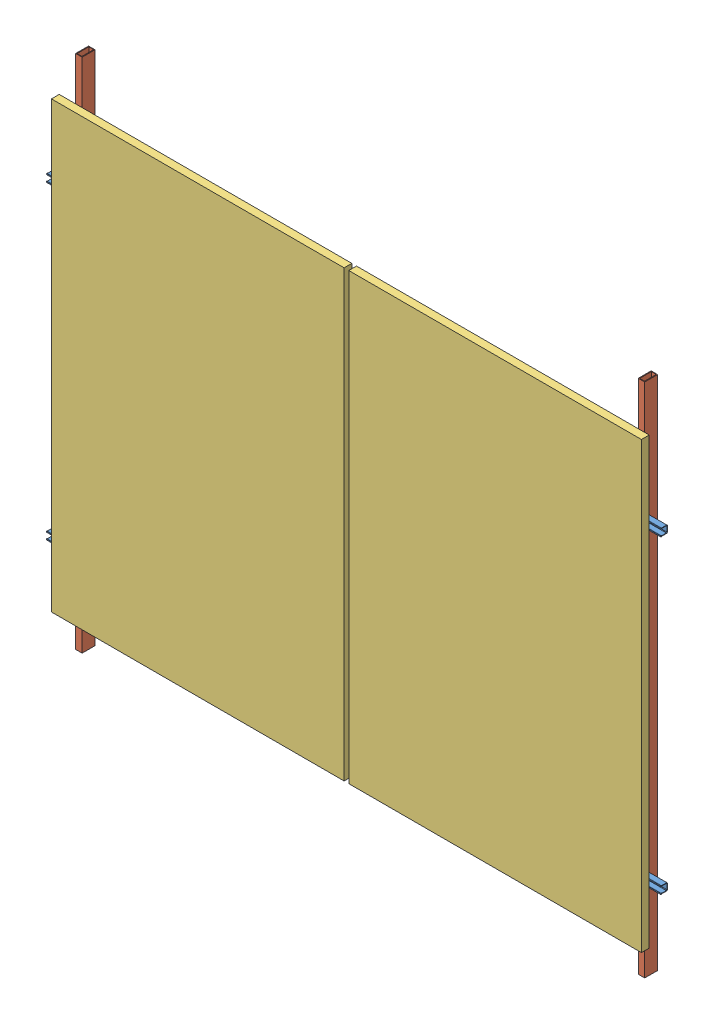
SolidWorks assembly fixation complete, configuration Défaut. Lengths in mm.
Overall size (2380 2000 105).
10 component instances, 3 part files, 6 mates.
Components (placement in the parent):
- rails-2: rails [Défaut] at (1934.6535 42.7775 1116.1785) x (0 1 0) z (1 0 0) size (30.2 25 200)
- charpente-1: charpente [Défaut] at (-129.1286 2691.6502 1082.4175) x (1 0 0) z (0 -1 0) size (2205 50 2000)
  - barre charpeinte-1: barre charpeinte [Défaut] at (-16.4034 -3.739 1000) size (25 50 2000)
  - barre charpeinte-2: barre charpeinte [Défaut] at (2163.5966 -3.739 1000) size (25 50 2000)
- rails-3: rails [Défaut] at (-245.3465 42.7775 1116.1785) x (0 1 0) z (1 0 0) size (30.2 25 200)
- rails-4: rails [Défaut] at (1934.6535 1242.7775 1116.1785) x (0 1 0) z (1 0 0) size (30.2 25 200)
- rails-5: rails [Défaut] at (-245.3465 1242.7775 1116.1785) x (0 1 0) z (1 0 0) size (30.2 25 200)
- planpanneaux-1: planpanneaux [Défaut] at (446.3874 769.5434 -578.3215) size (2286 1722 30)
  - JkM425N-54HL4-B-1: JkM425N-54HL4-B [Défaut] at (-76.123 -83.1343 1707) size (1134 1722 30)
  - JkM425N-54HL4-B-2: JkM425N-54HL4-B [Défaut] at (1075.877 -83.1343 1707) size (1134 1722 30)
Mates (geometry in assembly coordinates):
- Coïncidente2: coincident aligned: plane of rails-1 through (-35.3465 56.7775 191.5783) normal (0 1 0); plane of rails-2 through (2134.6535 56.7775 1116.1785) normal (0 1 0)
- Coïncidente3: coincident aligned: plane of rails-1 through (-35.3465 42.7775 179.0783) normal (0 0 -1); plane of rails-2 through (2134.6535 42.7775 1103.6785) normal (0 0 -1)
- Coïncidente4: coincident anti-aligned: plane of rails-2 through (2134.6535 42.7775 1103.6785) normal (0 0 -1); plane of charpente-1/barre charpeinte-2 through (2021.9681 -308.3498 1103.6785) normal (0 0 1)
- Coïncidente5: coincident anti-aligned: plane of charpente-1/barre charpeinte-1 through (-158.0319 -308.3498 1103.6785) normal (0 0 1); plane of rails-3 through (-45.3465 42.7775 1103.6785) normal (0 0 -1)
- Coaxiale2: concentric anti-aligned: cylinder of charpente-1/barre charpeinte-1 through (-145.3465 42.7775 1053.6785) axis (0 0 1) radius 3; cylinder of rails-3 through (-145.3465 42.7775 1128.6785) axis (0 0 -1) radius 3
- Coïncidente6: coincident anti-aligned: plane of rails-5 through (-45.3465 1242.7775 1128.6785) normal (0 0 1); plane of planpanneaux-1/JkM425N-54HL4-B-1 through (370.2644 686.409 1128.6785) normal (0 0 -1)
